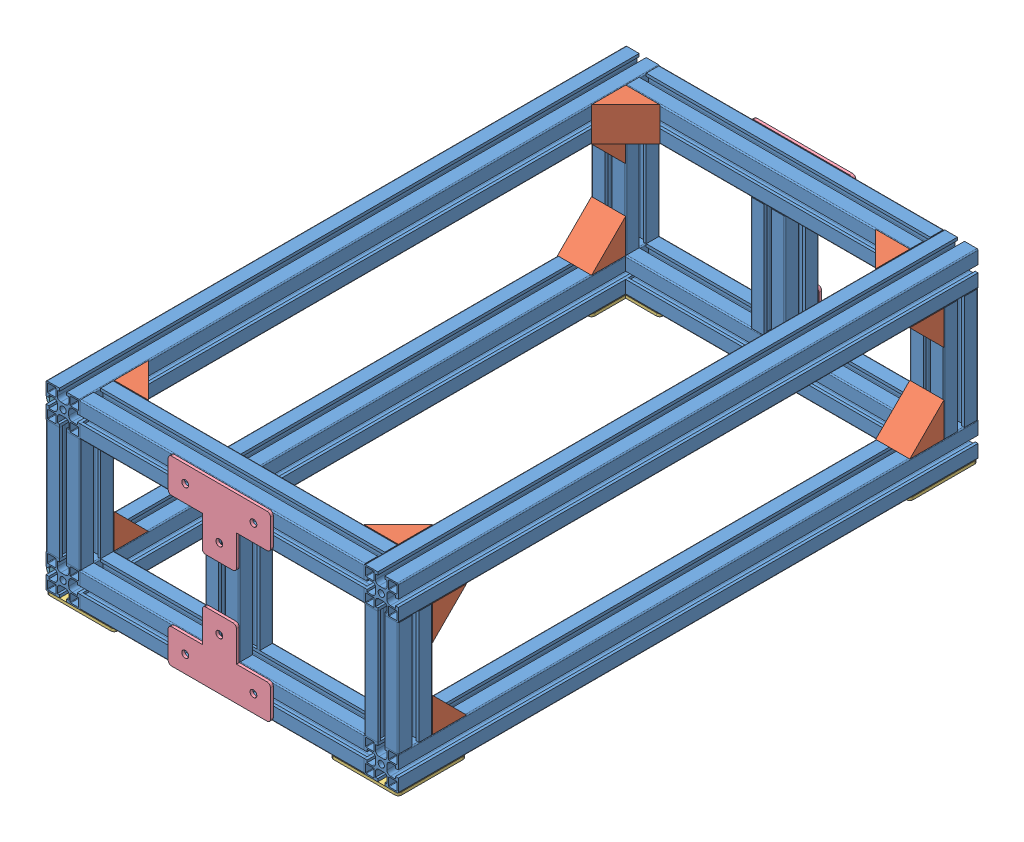
SolidWorks assembly stojak, configuration Default. Lengths in mm.
Overall size (315 162.5 515).
38 component instances, 5 part files, 74 mates.
Components (placement in the parent):
- profil_30x30-1: profil_30x30 [510] at (279.9393 324.2476 304.7304) size (30 30 510)
- profil_30x30-3: profil_30x30 [250] at (524.2314 345.6175 779.0225) x (0 0 -1) z (-1 0 0) size (30 30 250)
- profil_30x30-4: profil_30x30 [250] at (524.2314 345.6175 299.0225) x (0 0 -1) z (-1 0 0) size (30 30 250)
- profil_30x30-5: profil_30x30 [510] at (559.9393 324.2476 304.7304) size (30 30 510)
- profil_30x30-6: profil_30x30 [250] at (524.2314 475.6175 779.0225) x (0 0 -1) z (-1 0 0) size (30 30 250)
- profil_30x30-7: profil_30x30 [250] at (524.2314 475.6175 299.0225) x (0 0 -1) z (-1 0 0) size (30 30 250)
- profil_30x30-8: profil_30x30 [510] at (279.9393 454.2476 304.7304) size (30 30 510)
- profil_30x30-9: profil_30x30 [510] at (559.9393 454.2476 304.7304) size (30 30 510)
- profil_30x30-10: profil_30x30 [100] at (559.9393 449.9326 789.0454) x (1 0 0) z (0 -1 0) size (30 30 100)
- profil_30x30-11: profil_30x30 [100] at (559.9393 449.9326 309.0454) x (1 0 0) z (0 -1 0) size (30 30 100)
- profil_30x30-12: profil_30x30 [100] at (279.9393 449.9326 789.0454) x (1 0 0) z (0 -1 0) size (30 30 100)
- profil_30x30-13: profil_30x30 [100] at (279.9393 449.9326 309.0454) x (1 0 0) z (0 -1 0) size (30 30 100)
- profil_30x30-16: profil_30x30 [100] at (419.9393 449.9326 309.0454) x (1 0 0) z (0 -1 0) size (30 30 100)
- profil_30x30-17: profil_30x30 [100] at (419.9393 449.9326 789.0454) x (1 0 0) z (0 -1 0) size (30 30 100)
- katownik-2: katownik [Default] at (244.2314 367.5272 350.1358) x (0 0 -1) z (1 0 0) size (30 30 30)
- katownik-4: katownik [Default] at (244.2314 434.5272 352.325) x (0 1 0) z (1 0 0) size (30 30 30)
- katownik-5: katownik [Default] at (244.2314 432.338 769.325) x (0 0 1) z (1 0 0) size (30 30 30)
- katownik-6: katownik [Default] at (244.2314 365.338 767.1358) x (0 -1 0) z (1 0 0) size (30 30 30)
- katownik-7: katownik [Default] at (524.2314 365.338 767.1358) x (0 -1 0) z (1 0 0) size (30 30 30)
- katownik-8: katownik [Default] at (524.2314 432.338 769.325) x (0 0 1) z (1 0 0) size (30 30 30)
- katownik-9: katownik [Default] at (524.2314 434.5272 352.325) x (0 1 0) z (1 0 0) size (30 30 30)
- katownik-10: katownik [Default] at (524.2314 367.5272 350.1358) x (0 0 -1) z (1 0 0) size (30 30 30)
- katownik-11: katownik [Default] at (508.826 479.9326 352.325) x (1 0 0) z (0 -1 0) size (30 30 30)
- katownik-12: katownik [Default] at (291.826 479.9326 350.1358) x (0 0 -1) z (0 -1 0) size (30 30 30)
- katownik-18: katownik [Default] at (291.826 449.9326 769.325) x (0 0 1) z (0 1 0) size (30 30 30)
- katownik-19: katownik [Default] at (508.826 449.9326 767.1358) x (1 0 0) z (0 1 0) size (30 30 30)
- plaskownik_L-1: plaskownik_L [Default] at (536.7013 317.4326 779.5798) size (60 2.5 60)
- plaskownik_L-2: plaskownik_L [Default] at (519.0808 317.4326 322.2605) x (0 0 -1) z (1 0 0) size (60 2.5 60)
- plaskownik_L-3: plaskownik_L [Default] at (261.7615 317.4326 339.881) x (-1 0 0) z (0 0 -1) size (60 2.5 60)
- plaskownik_L-4: plaskownik_L [Default] at (279.382 317.4326 797.2002) x (0 0 1) z (-1 0 0) size (60 2.5 60)
- plaskownik_T-1: plaskownik_T [Default] at (401.7615 355.0832 304.7304) x (-1 0 0) z (0 -1 0) size (90 2.5 60)
- plaskownik_T-2: plaskownik_T [Default] at (396.7013 444.782 304.7304) x (1 0 0) z (0 1 0) size (90 2.5 60)
- plaskownik_T-3: plaskownik_T [Default] at (396.7013 355.0832 814.7304) x (1 0 0) z (0 -1 0) size (90 2.5 60)
- plaskownik_T-4: plaskownik_T [Default] at (396.7013 444.782 817.2304) x (1 0 0) z (0 1 0) size (90 2.5 60)
- nozka-1: nozka [Default] at (244.2314 334.9326 319.7304) x (0 0 -1) z (0 1 0) size (24 5 24)
- nozka-2: nozka [Default] at (244.2314 464.9326 319.7304) x (0 1 0) z (0 0 1) size (24 5 24)
- nozka-3: nozka [Default] at (244.2314 334.9326 799.7304) x (0 1 0) z (0 0 1) size (24 5 24)
- nozka-4: nozka [Default] at (244.2314 464.9326 799.7304) x (0 1 0) z (0 0 1) size (24 5 24)
Mates (geometry in assembly coordinates):
- Coincident1: coincident: line of profil_30x30-1 through (274.2314 338.0326 814.7304) axis (0 1 0); line of profil_30x30-3 through (274.2314 338.0326 814.7304) axis (0 1 0)
- Coincident2: coincident: plane of profil_30x30-1 through (279.9393 349.9326 814.7304) normal (0 1 0); plane of profil_30x30-3 through (274.2314 349.9326 779.0225) normal (0 1 0)
- Coincident3: coincident: line of profil_30x30-1 through (274.2314 338.0326 304.7304) axis (0 1 0); line of profil_30x30-4 through (274.2314 338.0326 304.7304) axis (0 1 0)
- Coincident4: coincident: plane of profil_30x30-1 through (279.9393 349.9326 814.7304) normal (0 1 0); plane of profil_30x30-4 through (274.2314 349.9326 299.0225) normal (0 1 0)
- Coincident5: coincident: line of profil_30x30-3 through (524.2314 338.0326 814.7304) axis (0 1 0); line of profil_30x30-5 through (524.2314 338.0326 814.7304) axis (0 1 0)
- Coincident6: coincident: plane of profil_30x30-3 through (274.2314 349.9326 779.0225) normal (0 1 0); plane of profil_30x30-5 through (559.9393 349.9326 814.7304) normal (0 1 0)
- Coincident7: coincident: line of profil_30x30-6 through (274.2314 468.0326 814.7304) axis (0 1 0); line of profil_30x30-8 through (274.2314 468.0326 814.7304) axis (0 1 0)
- Coincident8: coincident: plane of profil_30x30-7 through (274.2314 479.9326 299.0225) normal (0 1 0); plane of profil_30x30-8 through (279.9393 479.9326 814.7304) normal (0 1 0)
- Coincident9: coincident: line of profil_30x30-7 through (274.2314 468.0326 304.7304) axis (0 1 0); line of profil_30x30-8 through (274.2314 468.0326 304.7304) axis (0 1 0)
- Coincident10: coincident: plane of profil_30x30-6 through (274.2314 479.9326 779.0225) normal (0 1 0); plane of profil_30x30-8 through (279.9393 479.9326 814.7304) normal (0 1 0)
- Coincident11: coincident: line of profil_30x30-6 through (524.2314 468.0326 814.7304) axis (0 1 0); line of profil_30x30-9 through (524.2314 468.0326 814.7304) axis (0 1 0)
- Coincident12: coincident: plane of profil_30x30-6 through (274.2314 479.9326 779.0225) normal (0 1 0); plane of profil_30x30-9 through (559.9393 479.9326 814.7304) normal (0 1 0)
- Coincident13: coincident: line of profil_30x30-5 through (542.3314 349.9326 814.7304) axis (1 0 0); line of profil_30x30-10 through (542.3314 349.9326 814.7304) axis (1 0 0)
- Coincident14: coincident: plane of profil_30x30-5 through (554.2314 324.2476 814.7304) normal (1 0 0); plane of profil_30x30-10 through (554.2314 349.9326 789.0454) normal (1 0 0)
- Coincident15: coincident: line of profil_30x30-9 through (542.3314 449.9326 814.7304) axis (1 0 0); line of profil_30x30-10 through (542.3314 449.9326 814.7304) axis (1 0 0)
- Coincident16: coincident: plane of profil_30x30-9 through (554.2314 454.2476 814.7304) normal (1 0 0); plane of profil_30x30-10 through (554.2314 349.9326 789.0454) normal (1 0 0)
- Coincident17: coincident: plane of profil_30x30-13 through (279.9393 349.9326 334.7304) normal (0 0 1); plane of katownik-2 through (274.2314 349.9326 334.7304) normal (0 0 -1)
- Coincident18: coincident: plane of profil_30x30-1 through (279.9393 349.9326 814.7304) normal (0 1 0); plane of katownik-2 through (274.2314 349.9326 364.7304) normal (0 -1 0)
- Coincident19: coincident: plane of profil_30x30-1 through (244.2314 324.2476 814.7304) normal (-1 0 0); plane of katownik-2 through (244.2314 367.5272 350.1358) normal (-1 0 0)
- Coincident20: coincident: plane of profil_30x30-13 through (279.9393 349.9326 334.7304) normal (0 0 1); plane of katownik-4 through (274.2314 419.9326 334.7304) normal (0 0 -1)
- Coincident21: coincident: plane of profil_30x30-8 through (279.9393 449.9326 814.7304) normal (0 -1 0); plane of katownik-4 through (274.2314 449.9326 334.7304) normal (0 1 0)
- Coincident22: coincident: plane of profil_30x30-8 through (244.2314 454.2476 814.7304) normal (-1 0 0); plane of katownik-4 through (244.2314 434.5272 352.325) normal (-1 0 0)
- Coincident23: coincident: plane of profil_30x30-12 through (279.9393 349.9326 784.7304) normal (0 0 -1); plane of katownik-5 through (274.2314 449.9326 784.7304) normal (0 0 1)
- Coincident24: coincident: plane of profil_30x30-8 through (279.9393 449.9326 814.7304) normal (0 -1 0); plane of katownik-5 through (274.2314 449.9326 754.7304) normal (0 1 0)
- Coincident25: coincident: plane of profil_30x30-8 through (244.2314 454.2476 814.7304) normal (-1 0 0); plane of katownik-5 through (244.2314 432.338 769.325) normal (-1 0 0)
- Coincident26: coincident: plane of profil_30x30-1 through (279.9393 349.9326 814.7304) normal (0 1 0); plane of katownik-6 through (274.2314 349.9326 784.7304) normal (0 -1 0)
- Coincident27: coincident: plane of profil_30x30-12 through (279.9393 349.9326 784.7304) normal (0 0 -1); plane of katownik-6 through (274.2314 379.9326 784.7304) normal (0 0 1)
- Coincident28: coincident: plane of profil_30x30-1 through (244.2314 324.2476 814.7304) normal (-1 0 0); plane of katownik-6 through (244.2314 365.338 767.1358) normal (-1 0 0)
- Coincident29: coincident: plane of profil_30x30-7 through (274.2314 475.6175 334.7304) normal (0 0 1); plane of katownik-11 through (494.2314 449.9326 334.7304) normal (0 0 -1)
- Coincident31: coincident: plane of profil_30x30-9 through (524.2314 454.2476 814.7304) normal (-1 0 0); plane of katownik-11 through (524.2314 449.9326 334.7304) normal (1 0 0)
- Coincident33: coincident: plane of profil_30x30-9 through (559.9393 479.9326 814.7304) normal (0 1 0); plane of katownik-11 through (508.826 479.9326 352.325) normal (0 1 0)
- Coincident34: coincident: plane of profil_30x30-7 through (274.2314 475.6175 334.7304) normal (0 0 1); plane of katownik-12 through (274.2314 449.9326 334.7304) normal (0 0 -1)
- Coincident35: coincident: plane of profil_30x30-8 through (274.2314 454.2476 814.7304) normal (1 0 0); plane of katownik-12 through (274.2314 449.9326 364.7304) normal (-1 0 0)
- Coincident36: coincident: plane of profil_30x30-8 through (279.9393 479.9326 814.7304) normal (0 1 0); plane of katownik-12 through (291.826 479.9326 350.1358) normal (0 1 0)
- Coincident38: coincident: plane of profil_30x30-6 through (274.2314 475.6175 784.7304) normal (0 0 -1); plane of katownik-18 through (274.2314 479.9326 784.7304) normal (0 0 1)
- Coincident39: coincident: plane of profil_30x30-8 through (274.2314 454.2476 814.7304) normal (1 0 0); plane of katownik-18 through (274.2314 479.9326 754.7304) normal (-1 0 0)
- Coincident40: coincident: plane of profil_30x30-6 through (274.2314 479.9326 779.0225) normal (0 1 0); plane of katownik-18 through (291.826 479.9326 769.325) normal (0 1 0)
- Coincident41: coincident: plane of profil_30x30-6 through (274.2314 475.6175 784.7304) normal (0 0 -1); plane of katownik-19 through (494.2314 479.9326 784.7304) normal (0 0 1)
- Coincident42: coincident: plane of profil_30x30-9 through (524.2314 454.2476 814.7304) normal (-1 0 0); plane of katownik-19 through (524.2314 479.9326 784.7304) normal (1 0 0)
- Coincident43: coincident: plane of profil_30x30-9 through (559.9393 479.9326 814.7304) normal (0 1 0); plane of katownik-19 through (508.826 479.9326 767.1358) normal (0 1 0)
- Coincident44: coincident: plane of profil_30x30-5 through (559.9393 319.9326 814.7304) normal (0 -1 0); plane of plaskownik_L-1 through (536.7013 319.9326 779.5798) normal (0 1 0)
- Coincident45: coincident: plane of profil_30x30-3 through (274.2314 345.6175 814.7304) normal (0 0 1); line of plaskownik_L-1 through (497.2314 319.9326 814.7304) axis (1 0 0)
- Coincident46: coincident: plane of profil_30x30-5 through (554.2314 324.2476 814.7304) normal (1 0 0); plane of plaskownik_L-1 through (554.2314 319.9326 754.7304) normal (1 0 0)
- Coincident47: coincident: plane of profil_30x30-4 through (274.2314 319.9326 299.0225) normal (0 -1 0); plane of plaskownik_L-2 through (519.0808 319.9326 322.2605) normal (0 1 0)
- Coincident48: coincident: plane of profil_30x30-4 through (274.2314 345.6175 304.7304) normal (0 0 -1); plane of plaskownik_L-2 through (494.2314 319.9326 304.7304) normal (0 0 -1)
- Coincident49: coincident: plane of profil_30x30-5 through (554.2314 324.2476 814.7304) normal (1 0 0); plane of plaskownik_L-2 through (554.2314 319.9326 334.7304) normal (1 0 0)
- Coincident50: coincident: plane of profil_30x30-3 through (274.2314 319.9326 779.0225) normal (0 -1 0); plane of plaskownik_L-4 through (279.382 319.9326 797.2002) normal (0 1 0)
- Coincident51: coincident: plane of profil_30x30-3 through (274.2314 345.6175 814.7304) normal (0 0 1); plane of plaskownik_L-4 through (304.2314 319.9326 814.7304) normal (0 0 1)
- Coincident52: coincident: plane of profil_30x30-1 through (244.2314 324.2476 814.7304) normal (-1 0 0); plane of plaskownik_L-4 through (244.2314 319.9326 784.7304) normal (-1 0 0)
- Coincident53: coincident: plane of profil_30x30-4 through (274.2314 319.9326 299.0225) normal (0 -1 0); plane of plaskownik_L-3 through (261.7615 319.9326 339.881) normal (0 1 0)
- Coincident54: coincident: plane of profil_30x30-4 through (274.2314 345.6175 304.7304) normal (0 0 -1); plane of plaskownik_L-3 through (274.2314 319.9326 304.7304) normal (0 0 -1)
- Coincident55: coincident: plane of profil_30x30-1 through (244.2314 324.2476 814.7304) normal (-1 0 0); plane of plaskownik_L-3 through (244.2314 319.9326 364.7304) normal (-1 0 0)
- Coincident56: coincident: plane of profil_30x30-7 through (274.2314 475.6175 304.7304) normal (0 0 -1); plane of plaskownik_T-2 through (396.7013 444.782 304.7304) normal (0 0 1)
- Coincident57: coincident: plane of profil_30x30-7 through (274.2314 479.9326 299.0225) normal (0 1 0); plane of plaskownik_T-2 through (414.2314 479.9326 302.2304) normal (0 1 0)
- Coincident58: coincident: plane of profil_30x30-16 through (414.2314 349.9326 309.0454) normal (1 0 0); plane of plaskownik_T-2 through (414.2314 419.9326 302.2304) normal (1 0 0)
- Coincident59: coincident: plane of profil_30x30-4 through (274.2314 345.6175 304.7304) normal (0 0 -1); plane of plaskownik_T-1 through (401.7615 355.0832 304.7304) normal (0 0 1)
- Coincident60: coincident: plane of profil_30x30-4 through (274.2314 319.9326 299.0225) normal (0 -1 0); plane of plaskownik_T-1 through (384.2314 319.9326 302.2304) normal (0 -1 0)
- Coincident61: coincident: plane of profil_30x30-16 through (414.2314 349.9326 309.0454) normal (1 0 0); plane of plaskownik_T-1 through (414.2314 379.9326 302.2304) normal (1 0 0)
- Coincident62: coincident: plane of profil_30x30-3 through (274.2314 345.6175 814.7304) normal (0 0 1); plane of plaskownik_T-3 through (396.7013 355.0832 814.7304) normal (0 0 -1)
- Coincident63: coincident: plane of profil_30x30-3 through (274.2314 319.9326 779.0225) normal (0 -1 0); plane of plaskownik_T-3 through (414.2314 319.9326 817.2304) normal (0 -1 0)
- Coincident64: coincident: plane of profil_30x30-17 through (414.2314 349.9326 789.0454) normal (1 0 0); plane of plaskownik_T-3 through (414.2314 379.9326 817.2304) normal (1 0 0)
- Coincident65: coincident: plane of profil_30x30-6 through (274.2314 475.6175 814.7304) normal (0 0 1); plane of plaskownik_T-4 through (396.7013 444.782 814.7304) normal (0 0 -1)
- Coincident66: coincident: plane of profil_30x30-17 through (414.2314 349.9326 789.0454) normal (1 0 0); plane of plaskownik_T-4 through (414.2314 419.9326 814.7304) normal (1 0 0)
- Coincident67: coincident: plane of profil_30x30-6 through (274.2314 479.9326 779.0225) normal (0 1 0); plane of plaskownik_T-4 through (414.2314 479.9326 814.7304) normal (0 1 0)
- Coincident69: coincident: plane of profil_30x30-1 through (244.2314 324.2476 814.7304) normal (-1 0 0); plane of nozka-1 through (244.2314 334.9326 319.7304) normal (1 0 0)
- Concentric5: concentric: circle of profil_30x30-4; circle of nozka-1
- Coincident70: coincident: plane of profil_30x30-1 through (244.2314 324.2476 814.7304) normal (-1 0 0); plane of nozka-3 through (244.2314 334.9326 799.7304) normal (1 0 0)
- Coincident71: coincident: plane of profil_30x30-8 through (244.2314 454.2476 814.7304) normal (-1 0 0); plane of nozka-2 through (244.2314 464.9326 319.7304) normal (1 0 0)
- Coincident72: coincident: plane of profil_30x30-1 through (244.2314 324.2476 814.7304) normal (-1 0 0); plane of nozka-3 through (244.2314 334.9326 799.7304) normal (1 0 0)
- Concentric6: concentric: circle of profil_30x30-3; circle of nozka-3
- Concentric7: concentric: circle of profil_30x30-4; circle of nozka-1
- Concentric8: concentric: circle of profil_30x30-7; circle of nozka-2
- Coincident73: coincident: plane of profil_30x30-8 through (244.2314 454.2476 814.7304) normal (-1 0 0); plane of nozka-4 through (244.2314 464.9326 799.7304) normal (1 0 0)
- Concentric10: concentric: circle of profil_30x30-6; circle of nozka-4
